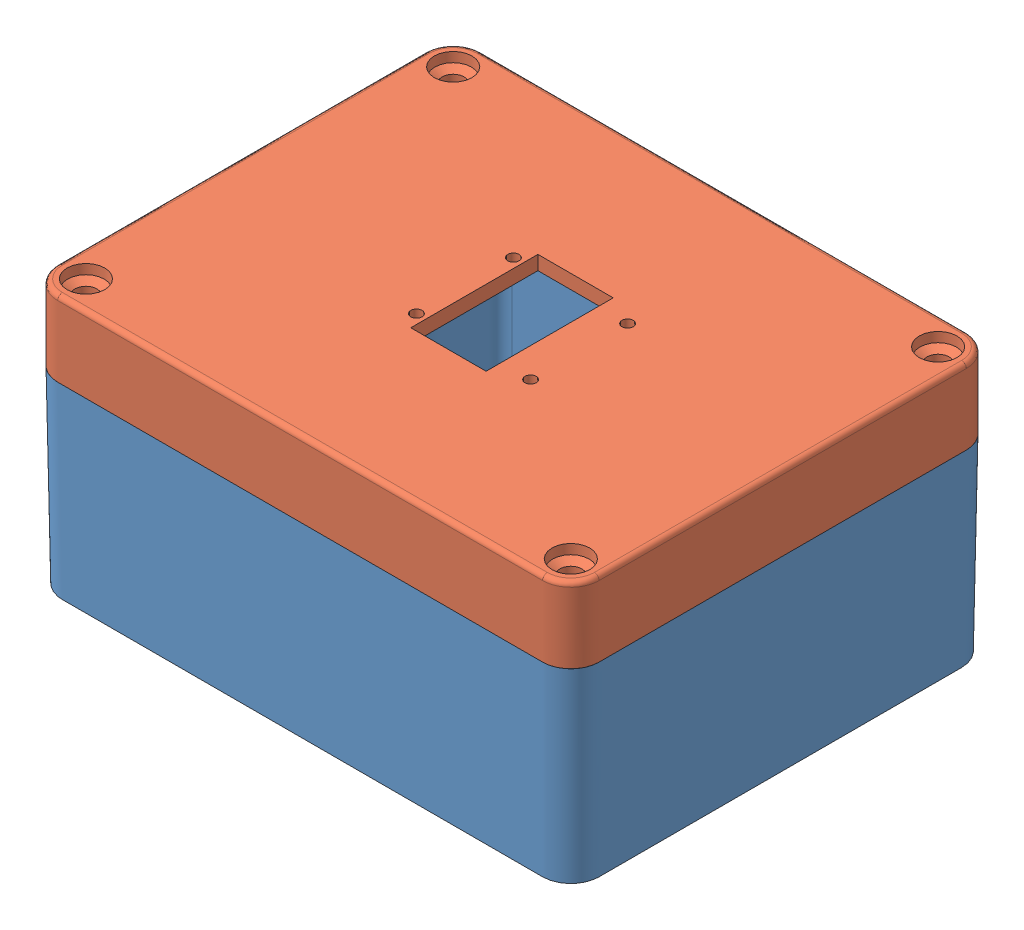
SolidWorks assembly Assieme cassetta, configuration Default. Lengths in mm.
Overall size (115.34 56.04 90.34).
2 component instances, 2 part files, 2 mates.
Components (placement in the parent):
- Scatola-1: Scatola [Default] at (-22.4191 -25.8542 0) size (115.01 41.55 90.01)
- Coperchio-1: Coperchio [Default] at (-22.4191 30.1458 0) size (115.34 16.04 90.34)
Mates (geometry in assembly coordinates):
- Coincidente1: coincident anti-aligned: plane of Scatola-1 through (-73.9191 14.1458 39) normal (0 1 0); plane of Coperchio-1 through (-73.9191 14.1458 39) normal (0 -1 0)
- Coincidente2: coincident aligned: circle of Scatola-1; circle of Coperchio-1
